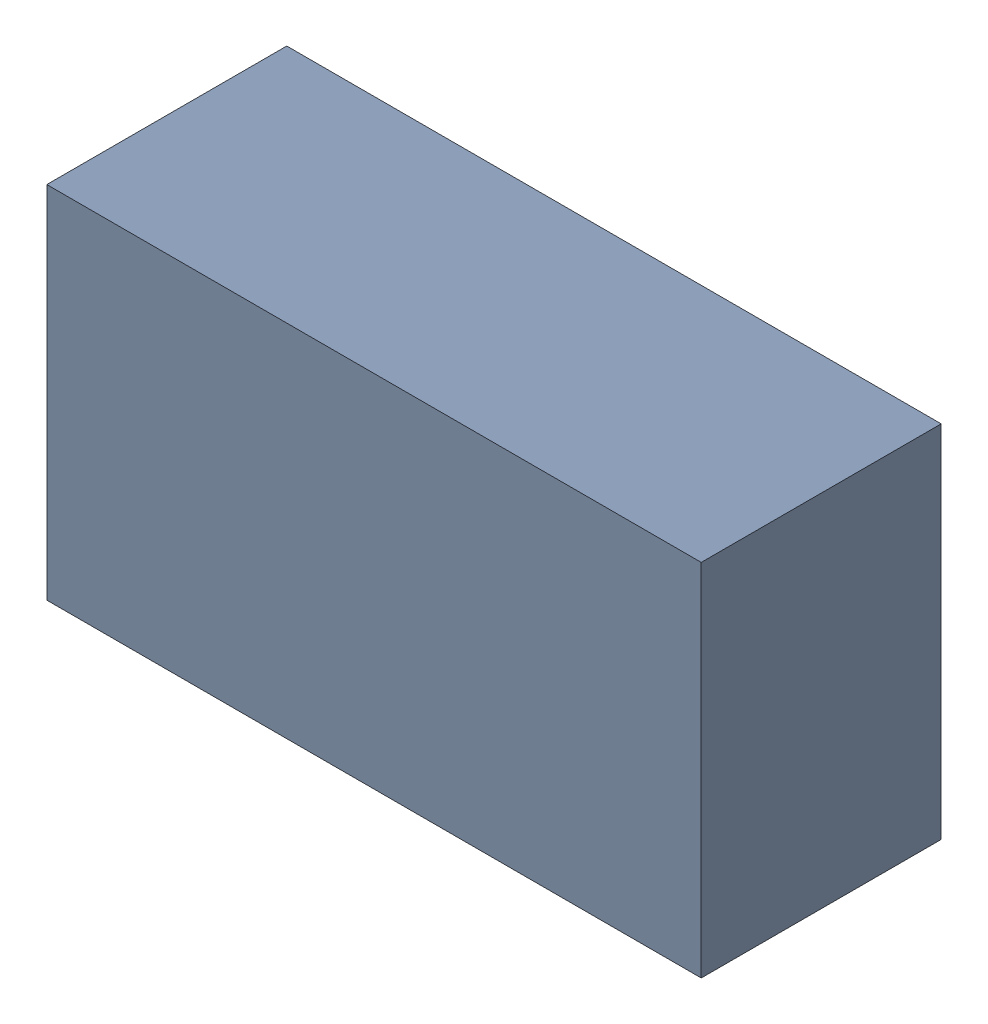
SolidWorks assembly D300_1PCB, configuration Default. Lengths in mm.
Overall size (3 1.65 1.1).
2 component instances, 1 part files, 0 mates.
Components (placement in the parent):
- 846483968-1: 846483968 [Default] at (155.7 105.3 0) size (3 1.65 1.1)
  - Extruded_7-1: Extruded_7 [Default] at origin size (3 1.65 1.1)
